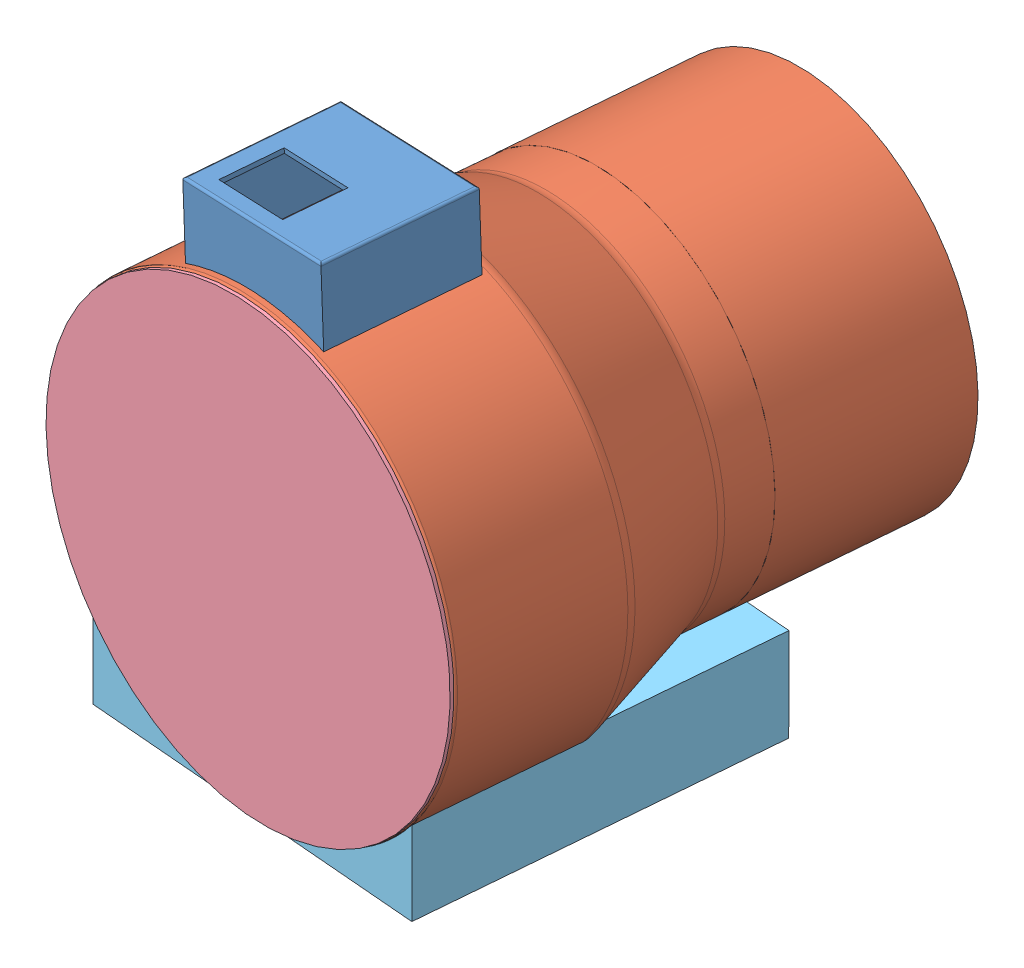
SolidWorks assembly SmokESP8266, configuration Défaut. Lengths in mm.
Overall size (235.64 231.18 266.79).
6 component instances, 5 part files, 7 mates.
Components (placement in the parent):
- coquesup-1: coquesup [Défaut] at (-165.459 143.385 104.0068) x (-0.082747 0.001875 0.996569) z (-0.043351 0.999045 -0.00548) size (63 65 32.06)
- reducteurdiametre-1: reducteurdiametre [Défaut] at (-151.8904 59.2331 -195.3086) x (0.986863 0.139392 0.081679) z (-0.082747 0.001875 0.996569) size (191 191 249.49)
  - reducteur-1: reducteur [Défaut] at (13.6998 -2.8102 264.5) size (191 191 223)
  - extracteur-1: extracteur [Défaut] at (13.6998 -2.8102 211.5067) x (-0.09603 -0.995378 0) z (0.995378 -0.09603 0) size (154 125 154)
  - filtre-1: filtre [Défaut] at (13.6998 -2.8102 274.5) size (190 190 61.5)
- support-1: support [Défaut] at (-228.2237 -36.6285 -16.9393) x (0.996571 0.000078 0.082747) z (-0.082747 0.001875 0.996569) size (150 40 150.12)
Mates (geometry in assembly coordinates):
- Parallèle1: parallel anti-aligned: plane of ? through (-7.67 -1.685 -65.977) normal (0 0 -1); plane of coquesup-1
- Coïncidente4: coincident anti-aligned: plane of ? through (-33.299 -32.6647 -65.977) normal (0 -1 0); plane of coquesup-1
- Coïncidente5: coincident anti-aligned: plane of ? through (-35.839 25.7553 -65.977) normal (-1 0 0); plane of coquesup-1
- Parallèle2: parallel aligned: plane of coquesup-1 through (-194.7364 176.961 69.9042) normal (0.082747 -0.001875 -0.996569); plane of reducteurdiametre-1/extracteur-1 through (-147.2075 58.5691 -83.0279) normal (0.082747 -0.001875 -0.996569)
- Parallèle3: parallel aligned: plane of coquesup-1 through (-167.063 180.3497 103.804) normal (-0.043351 0.999045 -0.00548); plane of reducteurdiametre-1/extracteur-1 through (-155.0475 133.154 -83.8192) normal (-0.043351 0.999045 -0.00548)
- Parallèle4: parallel aligned: plane of coquesup-1 through (-196.8931 176.8775 71.7321) normal (-0.995627 -0.043656 -0.082587); plane of reducteurdiametre-1/extracteur-1 through (-155.0475 133.154 -83.8192) normal (-0.995627 -0.043656 -0.082587)
- Parallèle5: parallel aligned: plane of reducteurdiametre-1/filtre-1 through (-165.7836 58.9901 140.6951) normal (-0.082747 0.001875 0.996569); plane of support-1 through (-240.6357 -36.3472 132.546) normal (-0.082747 0.001875 0.996569)
